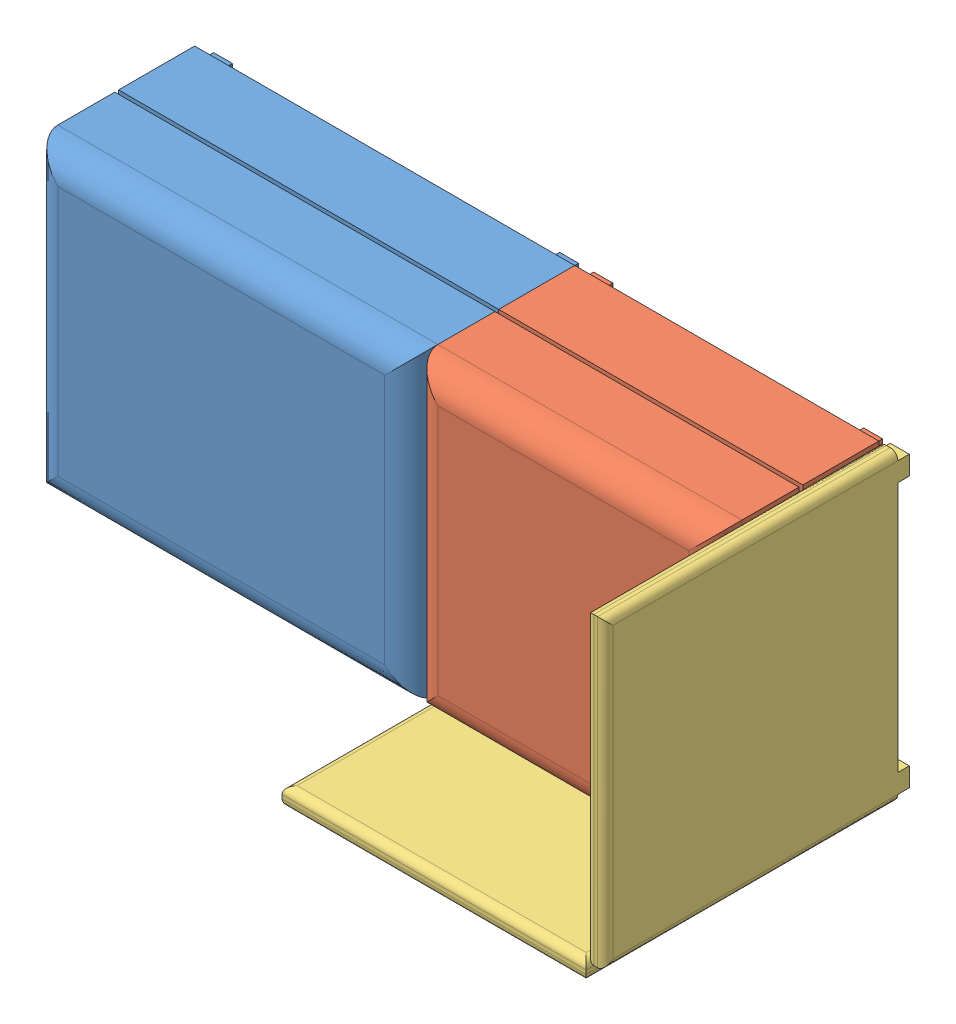
SolidWorks assembly Sofa-R, configuration Standard. Lengths in mm.
Overall size (1850 850 800).
4 component instances, 3 part files, 9 mates.
Components (placement in the parent):
- Sitzelement-1: Sitzelement [Standard] at (-51.9026 -321.2493 795.6126) x (0 -1 0) z (-1 0 0) size (800 460 1000)
- Sitzelement-mit-Aufb-1: Sitzelement-mit-Aufb [Standard] at (848.0974 -321.2493 795.6126) x (1 0 0) z (0 -1 0) size (800 460 800)
- Rückenstütze-80x80-2: Rückenstütze-80x80 [Standard] at (848.0974 -746.2493 765.6126) size (800 50 800)
- Rückenstütze-80x80-3: Rückenstütze-80x80 [Standard] at (1273.0974 -321.2493 765.6126) x (0 -1 0) z (0 0 1) size (800 50 800)
Mates (geometry in assembly coordinates):
- Deckungsgleich4: coincident aligned: plane of Sitzelement-1 through (-51.9026 -321.2493 765.6126) normal (0 0 -1); plane of Sitzelement-mit-Aufb-1 through (848.0974 -321.2493 765.6126) normal (0 0 -1)
- Deckungsgleich5: coincident anti-aligned: plane of Sitzelement-1 through (448.0974 78.7507 995.6126) normal (1 0 0); plane of Sitzelement-mit-Aufb-1 through (448.0974 -721.2493 995.6126) normal (-1 0 0)
- Deckungsgleich6: coincident aligned: plane of Sitzelement-1 through (-551.9026 78.7507 995.6126) normal (0 1 0); plane of Sitzelement-mit-Aufb-1 through (448.0974 78.7507 995.6126) normal (0 1 0)
- Deckungsgleich7: coincident aligned: plane of Sitzelement-mit-Aufb-1 through (848.0974 -321.2493 765.6126) normal (0 0 -1); plane of Rückenstütze-80x80-2 through (848.0974 -746.2493 765.6126) normal (0 0 -1)
- Deckungsgleich8: coincident aligned: plane of Sitzelement-mit-Aufb-1 through (848.0974 -321.2493 765.6126) normal (0 0 -1); plane of Rückenstütze-80x80-3 through (1273.0974 -321.2493 765.6126) normal (0 0 -1)
- Deckungsgleich10: coincident aligned: plane of Sitzelement-mit-Aufb-1 through (1248.0974 -721.2493 995.6126) normal (1 0 0); plane of Rückenstütze-80x80-2 through (1248.0974 -771.2493 1565.6126) normal (1 0 0)
- Deckungsgleich11: coincident anti-aligned: plane of Sitzelement-mit-Aufb-1 through (1248.0974 -721.2493 995.6126) normal (1 0 0); plane of Rückenstütze-80x80-3 through (1248.0974 58.7507 795.6126) normal (-1 0 0)
- Deckungsgleich12: coincident aligned: plane of Sitzelement-mit-Aufb-1 through (448.0974 78.7507 995.6126) normal (0 1 0); plane of Rückenstütze-80x80-3 through (1248.0974 78.7507 1565.6126) normal (0 1 0)
- Deckungsgleich14: coincident anti-aligned: plane of Sitzelement-mit-Aufb-1 through (448.0974 -721.2493 995.6126) normal (0 -1 0); plane of Rückenstütze-80x80-2 through (468.0974 -721.2493 795.6126) normal (0 1 0)
